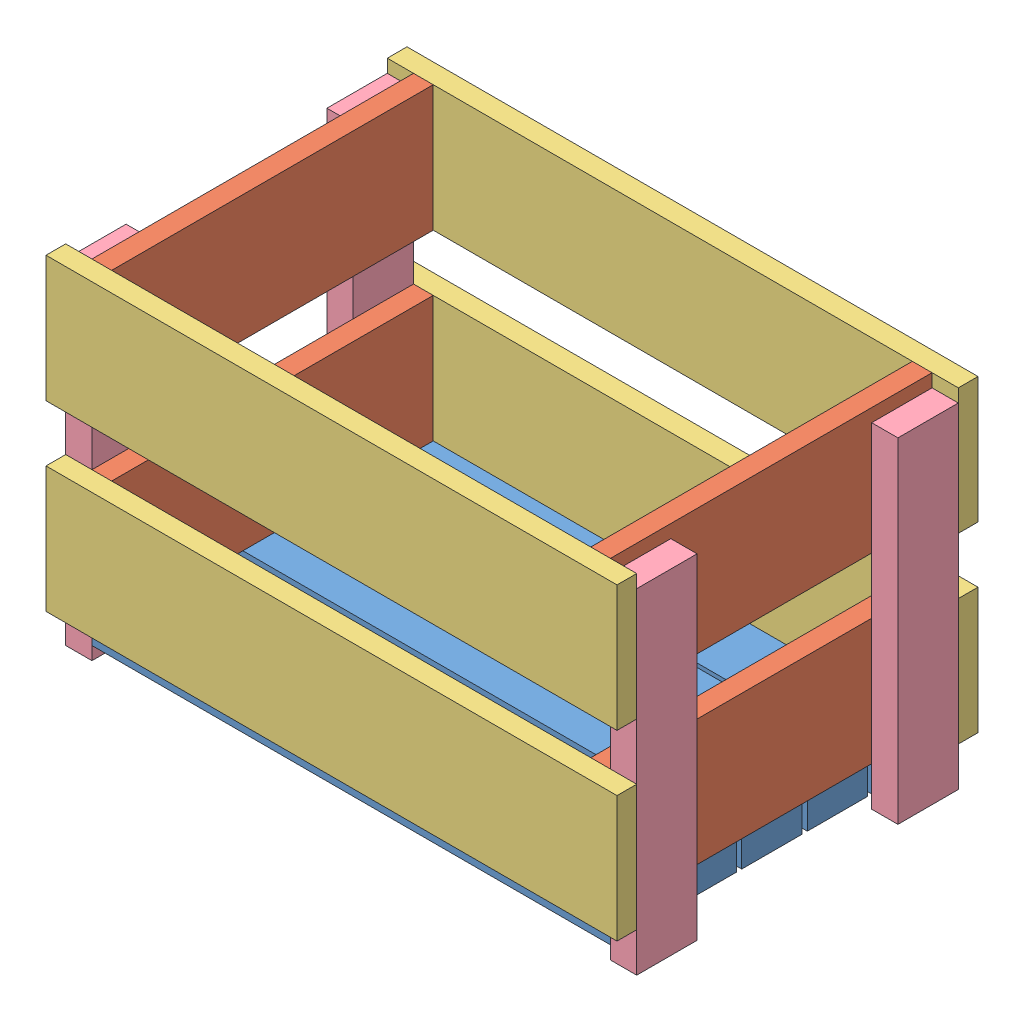
SolidWorks assembly Vinkasse, configuration Default. Lengths in mm.
Overall size (435 265 275).
41 component instances, 5 part files, 46 mates.
Components (placement in the parent):
- Bunnplank-1: Bunnplank [Default] at (0 -149 222) x (0 0 1) z (0 1 0) size (46 395 20)
- Bunnplank-10: Bunnplank [Default] at (0 -149 23) x (0 0 1) z (0 1 0) size (46 395 20)
- Vegg-kortside-1: Vegg-kortside [Default] at (387.5 48 245) x (0 1 0) z (-1 0 0) size (96 245 15)
- Vegg-langside-1: Vegg-langside [Default] at (-20 48 -7.5) x (0 -1 0) z (0 0 1) size (96 435 15)
- Vegg-langside-2: Vegg-langside [Default] at (415 48 252.5) x (0 1 0) z (0 0 1) size (96 435 15)
- Vegg-kortside-3: Vegg-kortside [Default] at (7.5 48 0) x (0 1 0) z (1 0 0) size (96 245 15)
- Vertikal_Stender-1: Vertikal_Stender [Default] at (405 -169 23) x (0 0 1) z (-1 0 0) size (46 255 20)
- Vertikal_Stender-2: Vertikal_Stender [Default] at (405 -169 222) x (0 0 1) z (-1 0 0) size (46 255 20)
- Vertikal_Stender-3: Vertikal_Stender [Default] at (-10 -169 222) x (0 0 -1) z (1 0 0) size (46 255 20)
- Vertikal_Stender-4: Vertikal_Stender [Default] at (-10 -169 23) x (0 0 -1) z (1 0 0) size (46 255 20)
- Vegg-kortside-5: Vegg-kortside [Default] at (7.5 -91 0) x (0 1 0) z (1 0 0) size (96 245 15)
- Vegg-langside-3: Vegg-langside [Default] at (415 -91 252.5) x (0 1 0) z (0 0 1) size (96 435 15)
- Vegg-langside-4: Vegg-langside [Default] at (-20 -91 -7.5) x (0 -1 0) z (0 0 1) size (96 435 15)
- Vegg-kortside-6: Vegg-kortside [Default] at (387.5 -91 245) x (0 1 0) z (-1 0 0) size (96 245 15)
- Dahls-1: Dahls [Default] at (41.8133 71.3082 215.5) size (59 225 59) (hidden)
- Dahls-2: Dahls [Default] at (41.8133 71.3082 154) size (59 225 59) (hidden)
- Dahls-3: Dahls [Default] at (41.8133 71.3082 92.5) size (59 225 59) (hidden)
- Dahls-4: Dahls [Default] at (41.8133 71.3082 31) size (59 225 59) (hidden)
- Dahls-5: Dahls [Default] at (103.3133 71.3082 215.5) size (59 225 59) (hidden)
- Dahls-6: Dahls [Default] at (103.3133 71.3082 154) size (59 225 59) (hidden)
- Dahls-7: Dahls [Default] at (103.3133 71.3082 92.5) size (59 225 59) (hidden)
- Dahls-8: Dahls [Default] at (103.3133 71.3082 31) size (59 225 59) (hidden)
- Dahls-9: Dahls [Default] at (164.8133 71.3082 215.5) size (59 225 59) (hidden)
- Dahls-10: Dahls [Default] at (164.8133 71.3082 154) size (59 225 59) (hidden)
- Dahls-11: Dahls [Default] at (164.8133 71.3082 92.5) size (59 225 59) (hidden)
- Dahls-12: Dahls [Default] at (164.8133 71.3082 31) size (59 225 59) (hidden)
- Dahls-13: Dahls [Default] at (226.3133 71.3082 215.5) size (59 225 59) (hidden)
- Dahls-14: Dahls [Default] at (226.3133 71.3082 154) size (59 225 59) (hidden)
- Dahls-15: Dahls [Default] at (226.3133 71.3082 92.5) size (59 225 59) (hidden)
- Dahls-16: Dahls [Default] at (226.3133 71.3082 31) size (59 225 59) (hidden)
- Dahls-17: Dahls [Default] at (287.8133 71.3082 215.5) size (59 225 59) (hidden)
- Dahls-18: Dahls [Default] at (287.8133 71.3082 154) size (59 225 59) (hidden)
- Dahls-19: Dahls [Default] at (287.8133 71.3082 92.5) size (59 225 59) (hidden)
- Dahls-20: Dahls [Default] at (287.8133 71.3082 31) size (59 225 59) (hidden)
- Dahls-21: Dahls [Default] at (349.3133 71.3082 215.5) size (59 225 59) (hidden)
- Dahls-22: Dahls [Default] at (349.3133 71.3082 154) size (59 225 59) (hidden)
- Dahls-23: Dahls [Default] at (349.3133 71.3082 92.5) size (59 225 59) (hidden)
- Dahls-24: Dahls [Default] at (349.3133 71.3082 31) size (59 225 59) (hidden)
- Bunnplank-11: Bunnplank [Default] at (0 -149 172) x (0 0 1) z (0 1 0) size (46 395 20)
- Bunnplank-12: Bunnplank [Default] at (0 -149 122) x (0 0 1) z (0 1 0) size (46 395 20)
- Bunnplank-13: Bunnplank [Default] at (0 -149 72) x (0 0 1) z (0 1 0) size (46 395 20)
Mates (geometry in assembly coordinates):
- Coincident1: coincident anti-aligned: plane of Vegg-langside-1 through (415 0 0) normal (0 -1 0)
- Coincident2: coincident aligned: plane of Vegg-langside-1 through (415 96 0) normal (0 0 1)
- Coincident3: coincident aligned: plane of Vegg-langside-1 through (415 96 0) normal (0 1 0); plane of Vegg-langside-2 through (-20 96 260) normal (0 1 0)
- Coincident4: coincident aligned: plane of Vegg-langside-1 through (415 48 -7.5) normal (1 0 0); plane of Vegg-langside-2 through (415 48 252.5) normal (1 0 0)
- Coincident6: coincident anti-aligned: plane of Vegg-kortside-1 through (387.5 48 0) normal (0 0 -1); plane of Vegg-langside-1 through (415 96 0) normal (0 0 1)
- Coincident7: coincident aligned: plane of Vegg-kortside-1 through (380 96 0) normal (0 1 0); plane of Vegg-langside-1 through (415 96 0) normal (0 1 0)
- Coincident8: coincident anti-aligned: plane of Vegg-kortside-1 through (387.5 48 245) normal (0 0 1); plane of Vegg-langside-2 through (-20 0 245) normal (0 0 -1)
- Coincident12: coincident anti-aligned: plane of Vegg-kortside-1 through (395 0 0) normal (1 0 0); plane of Vertikal_Stender-1 through (395 86 0) normal (-1 0 0)
- Coincident13: coincident anti-aligned: plane of Vegg-langside-1 through (415 96 0) normal (0 0 1); plane of Vertikal_Stender-1 through (395 86 0) normal (0 0 -1)
- Coincident14: coincident aligned: plane of Vegg-langside-1 through (415 48 -7.5) normal (1 0 0); plane of Vertikal_Stender-1 through (415 86 0) normal (1 0 0)
- Distance1: distance = 10 mm aligned: plane of Vegg-kortside-1 through (380 96 0) normal (0 1 0); plane of Vertikal_Stender-1 through (405 86 23) normal (0 1 0)
- Coincident17: coincident anti-aligned: plane of Vegg-kortside-1 through (395 0 0) normal (1 0 0); plane of Vertikal_Stender-2 through (395 86 199) normal (-1 0 0)
- Coincident18: coincident anti-aligned: plane of Vegg-langside-2 through (-20 0 245) normal (0 0 -1); plane of Vertikal_Stender-2 through (395 86 245) normal (0 0 1)
- Distance2: distance = 10 mm aligned: plane of Vertikal_Stender-2 through (405 86 222) normal (0 1 0); plane of Vegg-kortside-1 through (380 96 0) normal (0 1 0)
- Coincident20: coincident anti-aligned: plane of Vegg-kortside-3 through (0 0 245) normal (-1 0 0); plane of Vertikal_Stender-4 through (0 86 46) normal (1 0 0)
- Distance3: distance = 10 mm aligned: plane of Vegg-kortside-3 through (15 96 245) normal (0 1 0); plane of Vertikal_Stender-3 through (-10 86 222) normal (0 1 0)
- Distance4: distance = 10 mm aligned: plane of Vertikal_Stender-4 through (-10 86 23) normal (0 1 0); plane of Vegg-kortside-3 through (15 96 245) normal (0 1 0)
- Coincident21: coincident anti-aligned: plane of Vertikal_Stender-3 through (0 86 245) normal (1 0 0); plane of Vegg-kortside-3 through (0 0 245) normal (-1 0 0)
- Coincident22: coincident aligned: plane of Vegg-kortside-3 through (7.5 48 0) normal (0 0 -1); plane of Vertikal_Stender-4 through (0 86 0) normal (0 0 -1)
- Coincident23: coincident aligned: plane of Vertikal_Stender-3 through (0 86 245) normal (0 0 1); plane of Vegg-kortside-3 through (7.5 48 245) normal (0 0 1)
- Coincident24: coincident aligned: plane of Vegg-langside-2 through (-20 48 252.5) normal (-1 0 0); plane of Vertikal_Stender-3 through (-20 86 245) normal (-1 0 0)
- Coincident25: coincident anti-aligned: plane of Vegg-langside-2 through (-20 0 245) normal (0 0 -1); plane of Vegg-kortside-3 through (7.5 48 245) normal (0 0 1)
- Coincident26: coincident aligned: plane of Vegg-langside-2 through (-20 96 260) normal (0 1 0); plane of Vegg-kortside-3 through (15 96 245) normal (0 1 0)
- Coincident27: coincident anti-aligned: plane of Vegg-kortside-4 through (-184.7537 703.5616 1329.9681) normal (1 0 0); plane of Vertikal_Stender-6 through (-184.7537 789.5616 1533.9681) normal (-1 0 0)
- Distance6: distance = 10 mm aligned: plane of Vertikal_Stender-6 through (-174.7537 789.5616 1556.9681) normal (0 1 0); plane of Vegg-kortside-4 through (-199.7537 799.5616 1329.9681) normal (0 1 0)
- Coincident29: coincident anti-aligned: plane of Vegg-langside-4 through (415 -43 0) normal (0 0 1); plane of Vegg-kortside-6 through (387.5 -91 0) normal (0 0 -1)
- Coincident30: coincident aligned: plane of Vegg-langside-4 through (415 -43 0) normal (0 1 0); plane of Vegg-kortside-6 through (380 -43 0) normal (0 1 0)
- Coincident31: coincident anti-aligned: plane of Vegg-langside-3 through (-20 -139 245) normal (0 0 -1); plane of Vegg-kortside-6 through (387.5 -91 245) normal (0 0 1)
- Coincident32: coincident aligned: plane of Vegg-langside-3 through (415 -91 252.5) normal (1 0 0); plane of Vegg-langside-4 through (415 -91 -7.5) normal (1 0 0)
- Coincident33: coincident aligned: plane of Vegg-langside-3 through (-20 -43 260) normal (0 1 0); plane of Vegg-langside-4 through (415 -43 0) normal (0 1 0)
- Coincident34: coincident anti-aligned: plane of Vegg-kortside-5 through (7.5 -91 245) normal (0 0 1); plane of Vegg-langside-3 through (-20 -139 245) normal (0 0 -1)
- Coincident35: coincident aligned: plane of Vegg-kortside-5 through (15 -43 245) normal (0 1 0); plane of Vegg-langside-3 through (-20 -43 260) normal (0 1 0)
- Coincident36: coincident anti-aligned: plane of Vertikal_Stender-2 through (395 86 199) normal (-1 0 0); plane of Vegg-kortside-6 through (395 -139 0) normal (1 0 0)
- Coincident37: coincident anti-aligned: plane of Vertikal_Stender-3 through (0 86 245) normal (1 0 0); plane of Vegg-kortside-5 through (0 -139 245) normal (-1 0 0)
- Coincident38: coincident anti-aligned: plane of Vertikal_Stender-1 through (395 86 0) normal (0 0 -1); plane of Vegg-langside-4 through (415 -43 0) normal (0 0 1)
- Coincident39: coincident aligned: plane of Vertikal_Stender-2 through (415 86 199) normal (1 0 0); plane of Vegg-langside-3 through (415 -91 252.5) normal (1 0 0)
- Coincident40: coincident anti-aligned: plane of Vertikal_Stender-3 through (0 86 245) normal (1 0 0); plane of Bunnplank-1 through (0 -149 222) normal (-1 0 0)
- Distance7: distance = 10 mm aligned: plane of Bunnplank-1 through (395 -159 199) normal (0 -1 0); plane of Vertikal_Stender-3 through (-10 -169 222) normal (0 -1 0)
- Coincident42: coincident aligned: plane of Vertikal_Stender-3 through (0 86 245) normal (0 0 1); plane of Bunnplank-1 through (395 -139 245) normal (0 0 1)
- Coincident43: coincident anti-aligned: plane of Vegg-langside-3 through (-20 -139 260) normal (0 -1 0); plane of Bunnplank-1 through (395 -139 199) normal (0 1 0)
- Coincident54: coincident anti-aligned: plane of Vegg-kortside-3 through (0 0 245) normal (-1 0 0)
- Tangent2: tangent anti-aligned: plane of Vegg-langside-3 through (-20 -139 245) normal (0 0 -1); cylinder of Dahls-1 through (44.5 -139 215.5) axis (0 -1 0) radius 29.5
- Tangent3: tangent anti-aligned: plane of Vegg-kortside-5 through (15 -139 245) normal (1 0 0); cylinder of Dahls-1 through (44.5 -139 215.5) axis (0 -1 0) radius 29.5
- Coincident56: coincident anti-aligned: plane of Vertikal_Stender-4 through (0 86 46) normal (1 0 0); plane of Bunnplank-10 through (0 -149 23) normal (-1 0 0)
- Coincident57: coincident anti-aligned: plane of Vegg-kortside-5 through (15 -139 245) normal (0 -1 0); plane of Bunnplank-10 through (395 -139 0) normal (0 1 0)
- Coincident58: coincident anti-aligned: plane of Vegg-langside-4 through (415 -43 0) normal (0 0 1); plane of Bunnplank-10 through (395 -139 0) normal (0 0 -1)
